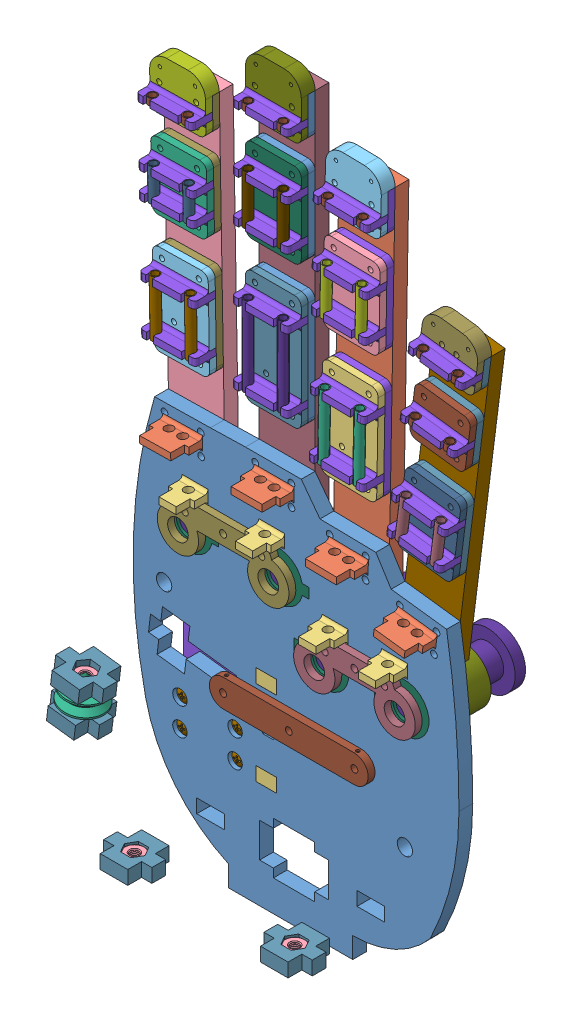
SolidWorks assembly palmTendonRouting_support, configuration Default. Lengths in mm.
Overall size (100.53 213.84 64.07).
220 component instances, 54 part files, 133 mates.
Components (placement in the parent):
- palmUp-1: palmUp [Default] at (29.1174 30.4931 80.2216) size (94.52 113.2 4)
- driverBaseFrame1-1: driverBaseFrame1 [Default] at (-2.9175 115.1932 80.2216) x (0.999847 0.017467 0) z (0.017467 -0.999847 0) size (11.5 12 4)
- driverBaseFrame1-2: driverBaseFrame1 [Default] at (23.5924 115.6931 80.2216) x (1 0 0) z (0 -1 0) size (11.5 12 4)
- driverBaseFrame1-3: driverBaseFrame1 [Default] at (45.1535 108.3901 80.2216) x (0.999848 -0.017452 0) z (-0.017452 -0.999848 0) size (11.5 12 4)
- driverBaseFrame1-4: driverBaseFrame1 [Default] at (65.1211 100.8452 80.2216) x (0.992117 -0.125312 0) z (-0.125312 -0.992117 0) size (11.5 12 4)
- driverBaseFrame2-1: driverBaseFrame2 [Default] at (-1948.2383 102.6443 -1374.6625) x (1 0 0) z (0 -1 0) size (7.5 12 4)
- driverBaseFrame2-2: driverBaseFrame2 [Default] at (1983.3157 100.6443 -1374.6625) x (-1 0 0) z (0 1 0) size (7.5 12 4)
- driverBaseFrame2-4: driverBaseFrame2 [Default] at (-1907.6963 87.8147 -1374.6625) x (1 0 0) z (0 -1 0) size (7.5 12 4)
- driverBaseFrame2-5: driverBaseFrame2 [Default] at (-1890.412 87.8147 -1374.6625) x (1 0 0) z (0 -1 0) size (7.5 12 4)
- index-1: index [Default] at (-52.494 173.2306 -0.0096) x (-0.999847 -0.017467 0) z (0 0 -1) size (16.2 99.16 12.01)
  - indexElastomer-1: indexElastomer [Default] at (-62.4059 -67.241 -80.2312) size (16.2 94.16 4)
  - indexPIP-1: indexPIP [Default] at (-62.4059 -42.8945 -84.2312) size (16.2 26.26 2)
  - indexMIP-1: indexMIP [Default] at (-62.4059 -8.6345 -84.2312) size (16.2 19.45 2)
  - indexDIP-1: indexDIP [Default] at (-62.4059 16.8205 -84.2312) size (16.2 14.95 4)
  - tubeDriver-6: tubeDriver [Default] at (-62.4059 20.8205 -80.2312) x (1 0 0) z (0 1 0) size (16.2 6 4)
  - tubeDriver-7: tubeDriver [Default] at (-62.4059 3.8205 -80.2312) x (1 0 0) z (0 1 0) size (16.2 6 4)
  - tubeDriver-8: tubeDriver [Default] at (-62.4059 -3.6345 -80.2312) x (1 0 0) z (0 1 0) size (16.2 6 4)
  - tubeDriver-9: tubeDriver [Default] at (-62.4059 -23.6345 -80.2312) x (1 0 0) z (0 1 0) size (16.2 6 4)
  - tubeDriver-10: tubeDriver [Default] at (-62.4059 -37.8945 -80.2312) x (1 0 0) z (0 1 0) size (16.2 6 4)
  - indexTube1-1: indexTube1 [Default] at (-49.2059 -21.6345 -86.4812) x (-0.964902 0 0.26261) z (0 -1 0) size (2.5 2.5 16.26)
  - indexTube1-2: indexTube1 [Default] at (-59.4059 -21.6345 -86.4812) x (-0.775159 0 0.631766) z (0 -1 0) size (2.5 2.5 16.26)
  - indexTube2-1: indexTube2 [Default] at (-49.2059 5.8205 -86.4812) x (0.360054 0 0.932932) z (0 -1 0) size (2.5 2.5 9.46)
  - indexTube2-2: indexTube2 [Default] at (-59.4059 5.8205 -86.4812) x (-0.658969 0 -0.75217) z (0 -1 0) size (2.5 2.5 9.46)
  - commonFingersTube-1: commonFingersTube [Default] at (-49.2059 22.8205 -86.4812) x (-0.856421 0 0.516277) z (0 -1 0) size (2.5 2.5 2)
  - commonFingersTube-2: commonFingersTube [Default] at (-59.4059 22.8205 -86.4812) x (-0.999231 0 0.039215) z (0 -1 0) size (2.5 2.5 2)
  - indexJointBase-1: indexJointBase [Default] at (-62.4059 -67.241 -82.2312) size (16.2 69.66 2)
- middle-1: middle [Default] at (34.8412 175.8995 -30.6566) size (16.2 113.14 12)
  - middleElastomer-1: middleElastomer [Default] at (-13.8237 -68.7065 106.8781) size (16.2 108.14 4)
  - middlePIP-1: middlePIP [Default] at (-13.8237 -44.2065 110.8781) size (16.2 33.21 2)
  - middleMIP-1: middleMIP [Default] at (-13.8237 -2.9965 110.8781) size (16.2 24.45 2)
  - middleDIP-1: middleDIP [Default] at (-5.7237 27.4535 110.8781) size (16.2 16.98 4)
  - tubeDriver-2: tubeDriver [Default] at (-13.8237 33.4535 110.8781) x (1 0 0) z (0 -1 0) size (16.2 6 4)
  - tubeDriver-3: tubeDriver [Default] at (-13.8237 16.4535 110.8781) x (1 0 0) z (0 -1 0) size (16.2 6 4)
  - tubeDriver-4: tubeDriver [Default] at (-13.8237 4.0035 110.8781) x (1 0 0) z (0 -1 0) size (16.2 6 4)
  - tubeDriver-5: tubeDriver [Default] at (-13.8237 -15.9965 110.8781) x (1 0 0) z (0 -1 0) size (16.2 6 4)
  - tubeDriver-6: tubeDriver [Default] at (-13.8237 -37.2065 110.8781) x (1 0 0) z (0 -1 0) size (16.2 6 4)
  - middleTube1-1: middleTube1 [Default] at (-10.8237 -39.2065 117.1281) x (1 0 0) z (0 1 0) size (2.5 2.5 23.21)
  - middleTube1-2: middleTube1 [Default] at (-0.6237 -39.2065 117.1281) x (1 0 0) z (0 1 0) size (2.5 2.5 23.21)
  - middleTube2-1: middleTube2 [Default] at (-10.8237 2.0035 117.1281) x (1 0 0) z (0 1 0) size (2.5 2.5 14.45)
  - middleTube2-2: middleTube2 [Default] at (-0.6237 2.0035 117.1281) x (1 0 0) z (0 1 0) size (2.5 2.5 14.45)
  - commonFingersTube-1: commonFingersTube [Default] at (-10.8237 31.4535 117.1281) x (1 0 0) z (0 1 0) size (2.5 2.5 2)
  - commonFingersTube-2: commonFingersTube [Default] at (-0.6237 31.4535 117.1281) x (1 0 0) z (0 1 0) size (2.5 2.5 2)
  - middleJointBase-1: middleJointBase [Default] at (-13.8237 -70.2065 110.8781) size (16.2 83.64 2)
- ring-1: ring [Default] at (23.5555 139.8292 -20.9472) x (-0.999848 0.017452 0) z (0 0 -1) size (16.2 107.96 12)
  - ringElastomer-1: ringElastomer [Default] at (-35.7683 -39.5573 -101.1688) size (16.2 102.96 4)
  - ringPIP-1: ringPIP [Default] at (-35.7683 -15.0573 -105.1688) size (16.2 29.14 2)
  - ringMIP-1: ringMIP [Default] at (-35.7683 22.0827 -105.1688) size (16.2 23.53 2)
  - ringDIP-1: ringDIP [Default] at (-19.5683 51.6077 -101.1688) x (-1 0 0) z (0 0 -1) size (16.2 16.8 4)
  - tubeDriver-6: tubeDriver [Default] at (-35.7683 55.6077 -101.1688) x (1 0 0) z (0 1 0) size (16.2 6 4)
  - tubeDriver-7: tubeDriver [Default] at (-35.7683 38.6077 -101.1688) x (1 0 0) z (0 1 0) size (16.2 6 4)
  - tubeDriver-8: tubeDriver [Default] at (-35.7683 27.0827 -101.1688) x (1 0 0) z (0 1 0) size (16.2 6 4)
  - tubeDriver-9: tubeDriver [Default] at (-35.7683 7.0827 -101.1688) x (1 0 0) z (0 1 0) size (16.2 6 4)
  - tubeDriver-10: tubeDriver [Default] at (-35.7683 -10.0573 -101.1688) x (1 0 0) z (0 1 0) size (16.2 6 4)
  - ringTube1-1: ringTube1 [Default] at (-22.5683 9.0827 -107.4188) x (1 0 0) z (0 -1 0) size (2.5 2.5 19.14)
  - ringTube1-2: ringTube1 [Default] at (-32.7683 9.0827 -107.4188) x (1 0 0) z (0 -1 0) size (2.5 2.5 19.14)
  - ringTube2-1: ringTube2 [Default] at (-22.5683 40.6077 -107.4188) x (1 0 0) z (0 -1 0) size (2.5 2.5 13.53)
  - ringTube2-2: ringTube2 [Default] at (-32.7683 40.6077 -107.4188) x (1 0 0) z (0 -1 0) size (2.5 2.5 13.53)
  - commonFingersTube-1: commonFingersTube [Default] at (-22.5683 57.6077 -107.4188) x (1 0 0) z (0 -1 0) size (2.5 2.5 2)
  - commonFingersTube-2: commonFingersTube [Default] at (-32.7683 57.6077 -107.4188) x (-0.448476 0 -0.893795) z (0 -1 0) size (2.5 2.5 2)
  - ringJointBase-1: ringJointBase [Default] at (-35.7683 -41.0573 -103.1688) size (16.2 78.46 2)
- pinky-1: pinky [Default] at (76.9532 164.3008 -0.0182) x (0.992117 -0.125312 0) z (0 0 1) size (16.2 89.09 12)
  - pinkyElastomer-1: pinkyElastomer [Default] at (-6.1366 -72.9381 76.2397) size (16.2 84.09 4)
  - pinkyPIP-1: pinkyPIP [Default] at (-6.1366 -48.4381 80.2397) size (16.2 21.74 2)
  - pinkyMIP-1: pinkyMIP [Default] at (-6.1366 -18.6981 80.2397) size (16.2 14.64 2)
  - pinkyDIP-1: pinkyDIP [Default] at (-6.1366 1.9469 80.2397) size (16.2 14.21 4)
  - tubeDriver-5: tubeDriver [Default] at (-6.1366 7.9469 80.2397) x (1 0 0) z (0 -1 0) size (16.2 6 4)
  - tubeDriver-7: tubeDriver [Default] at (-6.1366 -31.6981 80.2397) x (1 0 0) z (0 -1 0) size (16.2 6 4)
  - tubeDriver-8: tubeDriver [Default] at (-6.1366 -41.4381 80.2397) x (1 0 0) z (0 -1 0) size (16.2 6 4)
  - pinkyTube1-1: pinkyTube1 [Default] at (-3.1366 -43.4381 86.4897) x (1 0 0) z (0 1 0) size (2.5 2.5 11.74)
  - pinkyTube1-2: pinkyTube1 [Default] at (7.0634 -43.4381 86.4897) x (1 0 0) z (0 1 0) size (2.5 2.5 11.74)
  - tubeDriver-10: tubeDriver [Default] at (-6.1366 -10.3756 80.2397) x (1 0 0) z (0 -1 0) size (16.2 6 4)
  - commonFingersTube-1: commonFingersTube [Default] at (-3.1366 5.9469 86.4897) x (1 0 0) z (0 1 0) size (2.5 2.5 2)
  - commonFingersTube-2: commonFingersTube [Default] at (7.0634 5.9469 86.4897) x (1 0 0) z (0 1 0) size (2.5 2.5 2)
  - pinkyJointBase-1: pinkyJointBase [Default] at (-6.1366 -74.4381 80.2397) size (16.2 59.59 2)
  - commonFingersTube-3: commonFingersTube [Default] at (-3.1366 -12.3756 86.4897) x (1 0 0) z (0 1 0) size (2.5 2.5 2)
  - commonFingersTube-4: commonFingersTube [Default] at (7.0634 -12.3756 86.4897) x (1 0 0) z (0 1 0) size (2.5 2.5 2)
- buttonBase-1: buttonBase [Default] at (67.2648 77.3147 84.2216) x (0 -1 0) z (0 0 -1) size (16 16.84 9)
- buttonBase-2: buttonBase [Default] at (43.9805 77.3147 84.2216) x (0 -1 0) z (0 0 -1) size (16 16.84 9)
- buttonBase-3: buttonBase [Default] at (30.6388 92.1443 84.2216) x (0 1 0) z (0 0 -1) size (16 16.84 9)
- buttonBase-4: buttonBase [Default] at (4.4385 92.1443 84.2216) x (0 1 0) z (0 0 -1) size (16 16.84 9)
- buttonFrame-1: buttonFrame [Default] at (67.2648 77.3147 67.2216) x (-0.367754 -0.929923 0) z (0 0 1) size (16 16 8)
- buttonFrame-2: buttonFrame [Default] at (43.9805 77.3147 67.2216) x (-0.367754 -0.929923 0) z (0 0 1) size (16 16 8)
- buttonFrame-3: buttonFrame [Default] at (4.4385 92.1443 67.2216) x (-0.366273 -0.930508 0) z (0 0 1) size (16 16 8)
- buttonFrame-4: buttonFrame [Default] at (30.6388 92.1443 67.2216) x (-0.366273 -0.930508 0) z (0 0 1) size (16 16 8)
- buttonAxle-1: buttonAxle [Default] at (67.2648 77.3147 57.2216) size (16 16 27)
- buttonAxle-2: buttonAxle [Default] at (4.4385 92.1443 57.2216) size (16 16 27)
- buttonAxle-3: buttonAxle [Default] at (43.9805 77.3147 57.2216) x (-1 0 0) z (0 0 1) size (16 16 27)
- buttonAxle-4: buttonAxle [Default] at (30.6388 92.1443 57.2216) x (-1 0 0) z (0 0 1) size (16 16 27)
- parallel pin hardened_din-1: parallel pin hardened_din [Parallel Pin ISO 8734 - 2 x 14 - A - St] at (67.5898 69.8147 71.2178) x (0 1 0) z (-0.989175 0 -0.14674) size (14 2 2)
- parallel pin hardened_din-2: parallel pin hardened_din [Parallel Pin ISO 8734 - 2 x 14 - A - St] at (43.6555 69.8147 71.2178) x (0 1 0) z (-0.930242 0 0.366947) size (14 2 2)
- parallel pin hardened_din-3: parallel pin hardened_din [Parallel Pin ISO 8734 - 2 x 14 - A - St] at (4.7635 98.6443 71.2178) x (0 -1 0) z (0 0 1) size (14 2 2)
- parallel pin hardened_din-4: parallel pin hardened_din [Parallel Pin ISO 8734 - 2 x 14 - A - St] at (30.3138 98.6443 71.2178) x (0 -1 0) z (-0.297916 0 0.954592) size (14 2 2)
- Assem1-1: Assem1 [Default] at (68.1098 77.3321 69.8525) x (0.982823 0 0.184551) z (0 -1 0) size (9.07 23.24 9)
  - Spring Part-1: Spring Part [Default] at origin size (9 1 4.5)
  - Spring Part-7: Spring Part [Default] at (-0.0474 0.6138 0) x (0.988155 0.15346 0) z (0 0 -1) size (9 1 4.5)
  - Spring Part-8: Spring Part [Default] at (-0.0474 1.8415 0) x (0.988155 -0.15346 0) z (0 0 1) size (9 1 4.5)
  - Spring Part-9: Spring Part [Default] at (-0.0474 3.0692 0) x (0.988155 0.15346 0) z (0 0 -1) size (9 1 4.5)
  - Spring Part-10: Spring Part [Default] at (-0.0474 4.2969 0) x (0.988155 -0.15346 0) z (0 0 1) size (9 1 4.5)
  - Spring Part-11: Spring Part [Default] at (-0.0474 5.5246 0) x (0.988155 0.15346 0) z (0 0 -1) size (9 1 4.5)
  - Spring Part-12: Spring Part [Default] at (-0.0474 6.7522 0) x (0.988155 -0.15346 0) z (0 0 1) size (9 1 4.5) (hidden)
  - Spring Part-13: Spring Part [Default] at (-0.0474 7.9799 0) x (0.988155 0.15346 0) z (0 0 -1) size (9 1 4.5) (hidden)
  - Spring Part-14: Spring Part [Default] at (-0.0474 9.2076 0) x (0.988155 -0.15346 0) z (0 0 1) size (9 1 4.5) (hidden)
  - Spring Part-15: Spring Part [Default] at (-0.0474 10.4353 0) x (0.988155 0.15346 0) z (0 0 -1) size (9 1 4.5) (hidden)
  - Spring Part-16: Spring Part [Default] at (-0.0474 11.663 0) x (0.988155 -0.15346 0) z (0 0 1) size (9 1 4.5) (hidden)
  - Spring Part-17: Spring Part [Default] at (-0.0474 12.8906 0) x (0.988155 0.15346 0) z (0 0 -1) size (9 1 4.5) (hidden)
  - Spring Part-18: Spring Part [Default] at (-0.0474 14.1183 0) x (0.988155 -0.15346 0) z (0 0 1) size (9 1 4.5) (hidden)
  - Spring Part-19: Spring Part [Default] at (-0.0474 15.346 0) x (0.988155 0.15346 0) z (0 0 -1) size (9 1 4.5) (hidden)
  - Spring Part-20: Spring Part [Default] at (-0.0474 16.5737 0) x (0.988155 -0.15346 0) z (0 0 1) size (9 1 4.5) (hidden)
  - Spring Part-21: Spring Part [Default] at (-0.0474 17.8013 0) x (0.988155 0.15346 0) z (0 0 -1) size (9 1 4.5) (hidden)
  - Spring Part-22: Spring Part [Default] at (-0.0474 19.029 0) x (0.988155 -0.15346 0) z (0 0 1) size (9 1 4.5) (hidden)
  - Spring Part-23: Spring Part [Default] at (-0.0474 20.2567 0) x (0.988155 0.15346 0) z (0 0 -1) size (9 1 4.5) (hidden)
  - Spring Part-24: Spring Part [Default] at (-0.0474 21.4844 0) x (0.988155 -0.15346 0) z (0 0 1) size (9 1 4.5) (hidden)
  - Spring Part-25: Spring Part [Default] at (0 22.0982 0) x (1 0 0) z (0 0 -1) size (9 1 4.5) (hidden)
- Assem1-2: Assem1 [Default] at (43.2323 76.9505 75.7945) x (0.961864 0.191525 0.195284) z (-0.195284 0.980747 0) size (9.07 23.24 9)
  - Spring Part-1: Spring Part [Default] at origin size (9 1 4.5)
  - Spring Part-7: Spring Part [Default] at (-0.0474 0.6138 0) x (0.988155 0.15346 0) z (0 0 -1) size (9 1 4.5)
  - Spring Part-8: Spring Part [Default] at (-0.0474 1.8415 0) x (0.988155 -0.15346 0) z (0 0 1) size (9 1 4.5)
  - Spring Part-9: Spring Part [Default] at (-0.0474 3.0692 0) x (0.988155 0.15346 0) z (0 0 -1) size (9 1 4.5)
  - Spring Part-10: Spring Part [Default] at (-0.0474 4.2969 0) x (0.988155 -0.15346 0) z (0 0 1) size (9 1 4.5)
  - Spring Part-11: Spring Part [Default] at (-0.0474 5.5246 0) x (0.988155 0.15346 0) z (0 0 -1) size (9 1 4.5)
  - Spring Part-12: Spring Part [Default] at (-0.0474 6.7522 0) x (0.988155 -0.15346 0) z (0 0 1) size (9 1 4.5) (hidden)
  - Spring Part-13: Spring Part [Default] at (-0.0474 7.9799 0) x (0.988155 0.15346 0) z (0 0 -1) size (9 1 4.5) (hidden)
  - Spring Part-14: Spring Part [Default] at (-0.0474 9.2076 0) x (0.988155 -0.15346 0) z (0 0 1) size (9 1 4.5) (hidden)
  - Spring Part-15: Spring Part [Default] at (-0.0474 10.4353 0) x (0.988155 0.15346 0) z (0 0 -1) size (9 1 4.5) (hidden)
  - Spring Part-16: Spring Part [Default] at (-0.0474 11.663 0) x (0.988155 -0.15346 0) z (0 0 1) size (9 1 4.5) (hidden)
  - Spring Part-17: Spring Part [Default] at (-0.0474 12.8906 0) x (0.988155 0.15346 0) z (0 0 -1) size (9 1 4.5) (hidden)
  - Spring Part-18: Spring Part [Default] at (-0.0474 14.1183 0) x (0.988155 -0.15346 0) z (0 0 1) size (9 1 4.5) (hidden)
  - Spring Part-19: Spring Part [Default] at (-0.0474 15.346 0) x (0.988155 0.15346 0) z (0 0 -1) size (9 1 4.5) (hidden)
  - Spring Part-20: Spring Part [Default] at (-0.0474 16.5737 0) x (0.988155 -0.15346 0) z (0 0 1) size (9 1 4.5) (hidden)
  - Spring Part-21: Spring Part [Default] at (-0.0474 17.8013 0) x (0.988155 0.15346 0) z (0 0 -1) size (9 1 4.5) (hidden)
  - Spring Part-22: Spring Part [Default] at (-0.0474 19.029 0) x (0.988155 -0.15346 0) z (0 0 1) size (9 1 4.5) (hidden)
  - Spring Part-23: Spring Part [Default] at (-0.0474 20.2567 0) x (0.988155 0.15346 0) z (0 0 -1) size (9 1 4.5) (hidden)
  - Spring Part-24: Spring Part [Default] at (-0.0474 21.4844 0) x (0.988155 -0.15346 0) z (0 0 1) size (9 1 4.5) (hidden)
  - Spring Part-25: Spring Part [Default] at (0 22.0982 0) x (1 0 0) z (0 0 -1) size (9 1 4.5) (hidden)
- Assem1-3: Assem1 [Default] at (30.4884 91.6348 76.0217) x (1 0 0) z (0 1 0) size (9.07 23.24 9)
  - Spring Part-1: Spring Part [Default] at origin size (9 1 4.5)
  - Spring Part-7: Spring Part [Default] at (-0.0474 0.6138 0) x (0.988155 0.15346 0) z (0 0 -1) size (9 1 4.5)
  - Spring Part-8: Spring Part [Default] at (-0.0474 1.8415 0) x (0.988155 -0.15346 0) z (0 0 1) size (9 1 4.5)
  - Spring Part-9: Spring Part [Default] at (-0.0474 3.0692 0) x (0.988155 0.15346 0) z (0 0 -1) size (9 1 4.5)
  - Spring Part-10: Spring Part [Default] at (-0.0474 4.2969 0) x (0.988155 -0.15346 0) z (0 0 1) size (9 1 4.5)
  - Spring Part-11: Spring Part [Default] at (-0.0474 5.5246 0) x (0.988155 0.15346 0) z (0 0 -1) size (9 1 4.5)
  - Spring Part-12: Spring Part [Default] at (-0.0474 6.7522 0) x (0.988155 -0.15346 0) z (0 0 1) size (9 1 4.5) (hidden)
  - Spring Part-13: Spring Part [Default] at (-0.0474 7.9799 0) x (0.988155 0.15346 0) z (0 0 -1) size (9 1 4.5) (hidden)
  - Spring Part-14: Spring Part [Default] at (-0.0474 9.2076 0) x (0.988155 -0.15346 0) z (0 0 1) size (9 1 4.5) (hidden)
  - Spring Part-15: Spring Part [Default] at (-0.0474 10.4353 0) x (0.988155 0.15346 0) z (0 0 -1) size (9 1 4.5) (hidden)
  - Spring Part-16: Spring Part [Default] at (-0.0474 11.663 0) x (0.988155 -0.15346 0) z (0 0 1) size (9 1 4.5) (hidden)
  - Spring Part-17: Spring Part [Default] at (-0.0474 12.8906 0) x (0.988155 0.15346 0) z (0 0 -1) size (9 1 4.5) (hidden)
  - Spring Part-18: Spring Part [Default] at (-0.0474 14.1183 0) x (0.988155 -0.15346 0) z (0 0 1) size (9 1 4.5) (hidden)
  - Spring Part-19: Spring Part [Default] at (-0.0474 15.346 0) x (0.988155 0.15346 0) z (0 0 -1) size (9 1 4.5) (hidden)
  - Spring Part-20: Spring Part [Default] at (-0.0474 16.5737 0) x (0.988155 -0.15346 0) z (0 0 1) size (9 1 4.5) (hidden)
  - Spring Part-21: Spring Part [Default] at (-0.0474 17.8013 0) x (0.988155 0.15346 0) z (0 0 -1) size (9 1 4.5) (hidden)
  - Spring Part-22: Spring Part [Default] at (-0.0474 19.029 0) x (0.988155 -0.15346 0) z (0 0 1) size (9 1 4.5) (hidden)
  - Spring Part-23: Spring Part [Default] at (-0.0474 20.2567 0) x (0.988155 0.15346 0) z (0 0 -1) size (9 1 4.5) (hidden)
  - Spring Part-24: Spring Part [Default] at (-0.0474 21.4844 0) x (0.988155 -0.15346 0) z (0 0 1) size (9 1 4.5) (hidden)
  - Spring Part-25: Spring Part [Default] at (0 22.0982 0) x (1 0 0) z (0 0 -1) size (9 1 4.5) (hidden)
- Assem1-4: Assem1 [Default] at (3.643 90.6443 75.9726) x (1 0 0) z (0 1 0) size (9.07 23.24 9)
  - Spring Part-1: Spring Part [Default] at origin size (9 1 4.5)
  - Spring Part-7: Spring Part [Default] at (-0.0474 0.6138 0) x (0.988155 0.15346 0) z (0 0 -1) size (9 1 4.5)
  - Spring Part-8: Spring Part [Default] at (-0.0474 1.8415 0) x (0.988155 -0.15346 0) z (0 0 1) size (9 1 4.5)
  - Spring Part-9: Spring Part [Default] at (-0.0474 3.0692 0) x (0.988155 0.15346 0) z (0 0 -1) size (9 1 4.5)
  - Spring Part-10: Spring Part [Default] at (-0.0474 4.2969 0) x (0.988155 -0.15346 0) z (0 0 1) size (9 1 4.5)
  - Spring Part-11: Spring Part [Default] at (-0.0474 5.5246 0) x (0.988155 0.15346 0) z (0 0 -1) size (9 1 4.5)
  - Spring Part-12: Spring Part [Default] at (-0.0474 6.7522 0) x (0.988155 -0.15346 0) z (0 0 1) size (9 1 4.5) (hidden)
  - Spring Part-13: Spring Part [Default] at (-0.0474 7.9799 0) x (0.988155 0.15346 0) z (0 0 -1) size (9 1 4.5) (hidden)
  - Spring Part-14: Spring Part [Default] at (-0.0474 9.2076 0) x (0.988155 -0.15346 0) z (0 0 1) size (9 1 4.5) (hidden)
  - Spring Part-15: Spring Part [Default] at (-0.0474 10.4353 0) x (0.988155 0.15346 0) z (0 0 -1) size (9 1 4.5) (hidden)
  - Spring Part-16: Spring Part [Default] at (-0.0474 11.663 0) x (0.988155 -0.15346 0) z (0 0 1) size (9 1 4.5) (hidden)
  - Spring Part-17: Spring Part [Default] at (-0.0474 12.8906 0) x (0.988155 0.15346 0) z (0 0 -1) size (9 1 4.5) (hidden)
  - Spring Part-18: Spring Part [Default] at (-0.0474 14.1183 0) x (0.988155 -0.15346 0) z (0 0 1) size (9 1 4.5) (hidden)
  - Spring Part-19: Spring Part [Default] at (-0.0474 15.346 0) x (0.988155 0.15346 0) z (0 0 -1) size (9 1 4.5) (hidden)
  - Spring Part-20: Spring Part [Default] at (-0.0474 16.5737 0) x (0.988155 -0.15346 0) z (0 0 1) size (9 1 4.5) (hidden)
  - Spring Part-21: Spring Part [Default] at (-0.0474 17.8013 0) x (0.988155 0.15346 0) z (0 0 -1) size (9 1 4.5) (hidden)
  - Spring Part-22: Spring Part [Default] at (-0.0474 19.029 0) x (0.988155 -0.15346 0) z (0 0 1) size (9 1 4.5) (hidden)
  - Spring Part-23: Spring Part [Default] at (-0.0474 20.2567 0) x (0.988155 0.15346 0) z (0 0 -1) size (9 1 4.5) (hidden)
  - Spring Part-24: Spring Part [Default] at (-0.0474 21.4844 0) x (0.988155 -0.15346 0) z (0 0 1) size (9 1 4.5) (hidden)
  - Spring Part-25: Spring Part [Default] at (0 22.0982 0) x (1 0 0) z (0 0 -1) size (9 1 4.5) (hidden)
- SupportPulleyPalmUpAssem-1: SupportPulleyPalmUpAssem [Default] at (18.0404 39.4745 49.5054) size (10 28.63 11.6)
  - supportPulleyPalmUp2-1: supportPulleyPalmUp2 [Default] at (10.0404 13.9256 23.1162) size (7.5 28.63 2)
  - supportPulleyPalmUp-1: supportPulleyPalmUp [Default] at (12.0404 26.3656 34.7162) x (-1 0 0) z (0 -1 0) size (10 11.6 4)
  - supportPulleyPalmUp-2: supportPulleyPalmUp [Default] at (12.0404 1.7356 34.7162) x (-1 0 0) z (0 -1 0) size (10 11.6 4)
- hex nut style 1 gradeab_din-1: hex nut style 1 gradeab_din [Hexagon Nut ISO 4032 - M3 - D - S] at (27.442 52.7975 82.6216) x (0 1 0) z (0 0 1) size (5.5 6.35 2.4)
- plain washer 6902 type abc_din-1: plain washer 6902 type abc_din [DIN 6902-C3.2] at (28.0808 53.4001 80.2216) x (0 0 -1) z (0.195239 0.980756 0) size (0.8 7 7)
- pulley-1: pulley [Default] at (28.0808 53.4001 75.4216) x (0.991013 -0.133768 0) z (0 0 1) size (12 12 4)
- plain washer 6902 type abc_din-2: plain washer 6902 type abc_din [DIN 6902-C3.2] at (28.0808 53.4001 75.4216) x (0 0 -1) z (0.978291 0.207235 0) size (0.8 7 7)
- socket head cap screw 4762_din-1: socket head cap screw 4762_din [ISO 4762 M3 x 10 --- 10S] at (28.0808 53.4001 69.6216) x (0 0 1) z (-0.999894 -0.01457 0) size (13 5.5 5.5)
- baseHerkulex-1: baseHerkulex [Default] at (-4.9352 30.4931 70.2216) size (31 58.5 17.5)
- pan head cross recess screw_din-1: pan head cross recess screw_din [ISO 7045 - M2 x 10 - Z --- 10S] at (18.0174 47.3687 83.8216) x (0 0 -1) z (0.086476 0.996254 0) size (11.57 4 4)
- pan head cross recess screw_din-2: pan head cross recess screw_din [ISO 7045 - M2 x 10 - Z --- 10S] at (18.0174 39.3687 83.8216) x (0 0 -1) z (-0.029913 -0.999553 0) size (11.57 4 4)
- pan head cross recess screw_din-3: pan head cross recess screw_din [ISO 7045 - M2 x 10 - Z --- 10S] at (2.0174 39.3687 83.8216) x (0 0 -1) z (1 0 0) size (11.57 4 4)
- pan head cross recess screw_din-4: pan head cross recess screw_din [ISO 7045 - M2 x 10 - Z --- 10S] at (2.0174 47.3687 83.8216) x (0 0 -1) z (1 0 0) size (11.57 4 4)
- hex nut style 1 gradeab_din-2: hex nut style 1 gradeab_din [Hexagon Nut ISO 4032 - M2 - D - S] at (2.0174 39.3687 72.2216) x (0.792425 -0.60997 0) z (0 0 1) size (4 4.62 1.6)
- hex nut style 1 gradeab_din-3: hex nut style 1 gradeab_din [Hexagon Nut ISO 4032 - M2 - D - S] at (18.0174 47.3687 72.2216) x (0.098807 -0.995107 0) z (0 0 1) size (4 4.62 1.6)
- hex nut style 1 gradeab_din-4: hex nut style 1 gradeab_din [Hexagon Nut ISO 4032 - M2 - D - S] at (2.0174 47.3687 72.2216) size (4 4.62 1.6)
- hex nut style 1 gradeab_din-5: hex nut style 1 gradeab_din [Hexagon Nut ISO 4032 - M2 - D - S] at (18.0174 39.3687 72.2216) size (4 4.62 1.6)
- plasticSpacer-1: plasticSpacer [Default] at (2.0174 47.3687 76.2216) size (6 6 4)
- plasticSpacer-2: plasticSpacer [Default] at (18.0174 47.3687 76.2216) size (6 6 4)
- plasticSpacer-3: plasticSpacer [Default] at (18.0174 39.3687 76.2216) x (0.106039 0.994362 0) z (0 0 1) size (6 6 4)
- plasticSpacer-4: plasticSpacer [Default] at (2.0174 39.3687 76.2216) x (0.99764 -0.068656 0) z (0 0 1) size (6 6 4)
- whiffleetree-1: whiffleetree [Default] at (16.2286 39.1819 47.2015) x (1 0.000009 0) z (0 0 1) size (74.83 77 2)
  - mainBar-1: mainBar [Default] at (20.3524 18.4625 38.0201) size (46.08 8 2)
  - dynema1-1: dynema1 [Default] at (1.3104 55.9625 39.0201) x (0.250397 0 -0.968143) z (0 -1 0) size (1 1 34) (hidden)
  - barIndexMiddle-1: barIndexMiddle [Default] at (1.3104 58.4625 38.0201) size (38.2 14.5 2)
  - dynema2-1: dynema2 [Default] at (39.3944 21.9625 39.0201) x (0.365635 0 0.930758) z (0 1 0) size (1 1 19.17) (hidden)
  - barMiddlePinky-1: barMiddlePinky [Default] at (39.3944 43.6325 38.0201) size (35.28 14.5 2)
  - dynema3-1: dynema3 [Default] at (20.3524 14.9625 39.0201) x (0.922872 0 -0.385106) z (0 -1 0) size (1 1 30.5) (hidden)
- pulleyInsidePalmAssembled-1: pulleyInsidePalmAssembled [Default] at (-4.9042 46.692 121.0316) x (0.992536 -0.12195 0) z (0.12195 0.992536 0) size (14 13.03 13.6)
  - BasePulleyInsidePalm-1: BasePulleyInsidePalm [Default] at (-0.6961 4.81 7.3798) size (14 12 4)
  - BasePulleyInsidePalm-2: BasePulleyInsidePalm [Default] at (-0.6961 4.81 16.9798) size (14 12 4)
  - pulley-1: pulley [Default] at (3.3039 10.81 12.1798) x (0.995915 0.090298 0) z (0 0 1) size (12 12 4)
  - hex nut style 1 gradeab_din-2: hex nut style 1 gradeab_din [Hexagon Nut ISO 4032 - M3 - D - S] at (3.3916 10.6581 19.3798) x (0.866025 -0.5 0) z (0 0 1) size (5.5 6.35 2.4)
  - hex nut style 1 gradeab_din-3: hex nut style 1 gradeab_din [Hexagon Nut ISO 4032 - M3 - D - S] at (3.2162 10.6581 10.3798) x (0.866025 -0.5 0) z (0 0 1) size (5.5 6.35 2.4)
  - plain washer 6902 type abc_din-1: plain washer 6902 type abc_din [DIN 6902-C3.2] at (3.3039 10.81 16.9798) x (0 0 -1) z (0.829839 0.558003 0) size (0.8 7 7)
  - plain washer 6902 type abc_din-2: plain washer 6902 type abc_din [DIN 6902-C3.2] at (3.3039 10.81 11.3798) x (0 0 1) z (-1 0 0) size (0.8 7 7)
  - slotted set screw cone point_din-1: slotted set screw cone point_din [ISO 7434 - M3 x 12-S] at (3.3916 10.6581 7.9798) x (0 0 1) z (-0.968704 -0.248217 0) size (12 3 3)
- fastenFlangeAssembled-1: fastenFlangeAssembled [Default] at (3.2883 37.3377 94.7418) x (1 0 0) z (0 -1 0) size (14 12 4)
  - BasePulleyInsidePalm-1: BasePulleyInsidePalm [Default] at (3.6005 5.4798 12.8446) size (14 12 4)
  - hex nut style 1 gradeab_din-1: hex nut style 1 gradeab_din [Hexagon Nut ISO 4032 - M3 - D - S] at (7.6882 11.6317 15.8446) x (-0.866025 -0.5 0) z (0 0 1) size (5.5 6.35 2.4)
- fastenFlangeAssembled-2: fastenFlangeAssembled [Default] at (49.7883 37.3377 94.7418) x (1 0 0) z (0 -1 0) size (14 12 4)
  - BasePulleyInsidePalm-1: BasePulleyInsidePalm [Default] at (3.6005 5.4798 12.8446) size (14 12 4)
  - hex nut style 1 gradeab_din-1: hex nut style 1 gradeab_din [Hexagon Nut ISO 4032 - M3 - D - S] at (7.6882 11.6317 15.8446) x (-0.866025 -0.5 0) z (0 0 1) size (5.5 6.35 2.4)
Mates (geometry in assembly coordinates):
- Coincident1: coincident anti-aligned: plane of palmUp-1 through (-1.6321 113.2154 84.2216) normal (-0.017467 0.999847 0); plane of driverBaseFrame1-1 through (-2.8826 113.1935 80.2216) normal (0.017467 -0.999847 0)
- Coincident2: coincident anti-aligned: plane of palmUp-1 through (7.3666 113.3726 84.2216) normal (-0.999847 -0.017467 0); plane of driverBaseFrame1-1 through (7.3666 113.3726 84.2216) normal (0.999847 0.017467 0)
- Coincident3: coincident aligned: plane of palmUp-1 through (143.3195 75.6611 80.2216) normal (0 0 -1); plane of driverBaseFrame1-1 through (-1.6328 113.2154 80.2216) normal (0 0 -1)
- Coincident4: coincident anti-aligned: plane of palmUp-1 through (24.8424 113.6931 84.2216) normal (0 1 0); plane of driverBaseFrame1-2 through (23.5924 113.6931 80.2216) normal (0 -1 0)
- Coincident5: coincident anti-aligned: plane of palmUp-1 through (24.8424 115.6931 84.2216) normal (1 0 0); plane of driverBaseFrame1-2 through (24.8424 113.6931 84.2216) normal (-1 0 0)
- Coincident6: coincident aligned: plane of palmUp-1 through (143.3195 75.6611 80.2216) normal (0 0 -1); plane of driverBaseFrame1-2 through (24.8424 113.6931 80.2216) normal (0 0 -1)
- Coincident7: coincident aligned: plane of palmUp-1 through (143.3195 75.6611 80.2216) normal (0 0 -1); plane of driverBaseFrame1-3 through (46.3684 106.3686 80.2216) normal (0 0 -1)
- Coincident8: coincident anti-aligned: plane of palmUp-1 through (54.952 108.2191 84.2216) normal (-0.017452 -0.999848 0); plane of driverBaseFrame1-3 through (45.1535 108.3901 80.2216) normal (0.017452 0.999848 0)
- Coincident12: coincident anti-aligned: plane of palmUp-1 through (46.4033 108.3683 84.2216) normal (0.999848 -0.017452 0); plane of driverBaseFrame1-3 through (46.3684 106.3686 84.2216) normal (-0.999848 0.017452 0)
- Coincident13: coincident anti-aligned: plane of palmUp-1 through (66.1107 98.7043 84.2216) normal (0.125312 0.992117 0); plane of driverBaseFrame1-4 through (64.8705 98.861 80.2216) normal (-0.125312 -0.992117 0)
- Coincident14: coincident aligned: plane of palmUp-1 through (143.3195 75.6611 80.2216) normal (0 0 -1); plane of driverBaseFrame1-4 through (66.1107 98.7043 80.2216) normal (0 0 -1)
- Coincident15: coincident anti-aligned: plane of palmUp-1 through (66.3613 100.6886 84.2216) normal (0.992117 -0.125312 0); plane of driverBaseFrame1-4 through (66.1107 98.7043 84.2216) normal (-0.992117 0.125312 0)
- Coincident16: coincident anti-aligned: plane of palmUp-1 through (3.9385 100.6443 84.2216) normal (0 1 0); plane of driverBaseFrame2-1 through (-1948.2383 100.6443 -1374.6625) normal (0 -1 0)
- Coincident17: coincident aligned: plane of palmUp-1 through (143.3195 75.6611 80.2216) normal (0 0 -1); plane of driverBaseFrame2-1 through (3.9385 100.6443 80.2216) normal (0 0 -1)
- Coincident18: coincident anti-aligned: plane of palmUp-1 through (3.9385 102.6443 84.2216) normal (1 0 0); plane of driverBaseFrame2-1 through (3.9385 100.6443 84.2216) normal (-1 0 0)
- Distance1: distance = 0 mm aligned: plane of palmUp-1 through (143.3195 75.6611 80.2216) normal (0 0 -1); plane of driverBaseFrame2-2 through (31.1388 102.6443 80.2216) normal (0 0 -1)
- Coincident20: coincident anti-aligned: plane of palmUp-1 through (31.1388 100.6443 84.2216) normal (-1 0 0); plane of driverBaseFrame2-2 through (31.1388 102.6443 84.2216) normal (1 0 0)
- Coincident21: coincident anti-aligned: plane of palmUp-1 through (26.1388 102.6443 84.2216) normal (0 -1 0); plane of driverBaseFrame2-2 through (1983.3157 102.6443 -1374.6625) normal (0 1 0)
- Coincident22: coincident anti-aligned: plane of palmUp-1 through (44.4805 85.8147 84.2216) normal (0 1 0); plane of driverBaseFrame2-4 through (-1907.6963 85.8147 -1374.6625) normal (0 -1 0)
- Coincident23: coincident aligned: plane of palmUp-1 through (143.3195 75.6611 80.2216) normal (0 0 -1); plane of driverBaseFrame2-4 through (44.4805 85.8147 80.2216) normal (0 0 -1)
- Coincident24: coincident anti-aligned: plane of palmUp-1 through (49.4805 85.8147 84.2216) normal (-1 0 0); plane of driverBaseFrame2-4 through (49.4805 85.8147 84.2216) normal (1 0 0)
- Coincident25: coincident anti-aligned: plane of palmUp-1 through (61.7648 85.8147 84.2216) normal (0 1 0); plane of driverBaseFrame2-5 through (-1890.412 85.8147 -1374.6625) normal (0 -1 0)
- Coincident26: coincident aligned: plane of palmUp-1 through (143.3195 75.6611 80.2216) normal (0 0 -1); plane of driverBaseFrame2-5 through (61.7648 85.8147 80.2216) normal (0 0 -1)
- Coincident27: coincident anti-aligned: plane of palmUp-1 through (61.7648 87.8147 84.2216) normal (1 0 0); plane of driverBaseFrame2-5 through (61.7648 85.8147 84.2216) normal (-1 0 0)
- Concentric1: concentric anti-aligned: cylinder of palmUp-1 through (8.0553 116.8851 84.2216) axis (0 0 -1) radius 0.975; cylinder of index-1/indexElastomer-1 through (8.0553 116.8851 76.2216) axis (0 0 1) radius 0.5
- Concentric2: concentric anti-aligned: cylinder of palmUp-1 through (8.1601 110.886 84.2216) axis (0 0 -1) radius 0.975; cylinder of index-1/indexElastomer-1 through (8.1601 110.886 76.2216) axis (0 0 1) radius 0.5
- Coincident28: coincident anti-aligned: plane of palmUp-1 through (143.3195 75.6611 80.2216) normal (0 0 -1); plane of index-1/indexElastomer-1 through (11.0769 107.0899 80.2216) normal (0 0 1)
- Concentric3: concentric aligned: cylinder of palmUp-1 through (23.8674 111.1931 84.2216) axis (0 0 -1) radius 0.975; cylinder of middle-1/middleElastomer-1 through (23.8674 111.1931 80.2216) axis (0 0 -1) radius 0.52
- Concentric4: concentric aligned: circle of palmUp-1; circle of middle-1/middleElastomer-1
- Coincident29: coincident anti-aligned: plane of palmUp-1 through (143.3195 75.6611 80.2216) normal (0 0 -1); plane of middle-1/middleElastomer-1 through (21.0174 107.1931 80.2216) normal (0 0 1)
- Concentric5: concentric aligned: circle of palmUp-1; cylinder of ring-1/ringElastomer-1 through (45.3499 103.886 76.2216) axis (0 0 1) radius 0.5
- Concentric6: concentric anti-aligned: cylinder of palmUp-1 through (45.4546 109.8851 84.2216) axis (0 0 -1) radius 0.975; cylinder of ring-1/ringElastomer-1 through (45.4546 109.8851 76.2216) axis (0 0 1) radius 0.5
- Coincident30: coincident anti-aligned: plane of palmUp-1 through (143.3195 75.6611 80.2216) normal (0 0 -1); plane of ring-1/ringElastomer-1 through (58.628 99.6536 80.2216) normal (0 0 1)
- Concentric7: concentric aligned: cylinder of palmUp-1 through (65.0537 96.318 84.2216) axis (0 0 -1) radius 0.975; cylinder of pinky-1/pinkyElastomer-1 through (65.0537 96.318 80.2216) axis (0 0 -1) radius 0.52
- Concentric8: concentric anti-aligned: cylinder of palmUp-1 through (65.8055 102.2707 84.2216) axis (0 0 -1) radius 0.975; circle of pinky-1/pinkyElastomer-1
- Coincident31: coincident anti-aligned: plane of palmUp-1 through (143.3195 75.6611 80.2216) normal (0 0 -1); plane of pinky-1/pinkyElastomer-1 through (61.7249 92.7066 80.2216) normal (0 0 1)
- Concentric9: concentric anti-aligned: cylinder of palmUp-1 through (67.2648 77.3147 84.2216) axis (0 0 -1) radius 7; cylinder of buttonBase-1 through (67.2648 77.3147 80.2216) axis (0 0 1) radius 7
- Coincident32: coincident: moEndPointRef_w of palmUp-1; plane of buttonBase-1 through (60.4274 75.8147 80.2216) normal (0 -1 0)
- Coincident40: coincident anti-aligned: plane of palmUp-1 through (143.3195 75.6611 80.2216) normal (0 0 -1); plane of buttonBase-1 through (67.2648 77.3147 80.2216) normal (0 0 1)
- Concentric10: concentric anti-aligned: cylinder of palmUp-1 through (43.9805 77.3147 84.2216) axis (0 0 -1) radius 7; cylinder of buttonBase-2 through (43.9805 77.3147 80.2216) axis (0 0 1) radius 7
- Coincident34: coincident anti-aligned: plane of palmUp-1 through (35.1431 75.8147 84.2216) normal (0 1 0); plane of buttonBase-2 through (37.1431 75.8147 80.2216) normal (0 -1 0)
- Coincident41: coincident anti-aligned: plane of palmUp-1 through (143.3195 75.6611 80.2216) normal (0 0 -1); plane of buttonBase-2 through (43.9805 77.3147 80.2216) normal (0 0 1)
- Concentric11: concentric anti-aligned: cylinder of palmUp-1 through (30.6388 92.1443 84.2216) axis (0 0 -1) radius 7; cylinder of buttonBase-3 through (30.6388 92.1443 80.2216) axis (0 0 1) radius 7
- Coincident37: coincident anti-aligned: plane of palmUp-1 through (39.4762 90.6443 84.2216) normal (0 1 0); plane of buttonBase-3 through (38.497 90.6443 80.2216) normal (0 -1 0)
- Coincident42: coincident anti-aligned: plane of palmUp-1 through (143.3195 75.6611 80.2216) normal (0 0 -1); plane of buttonBase-3 through (30.6388 92.1443 80.2216) normal (0 0 1)
- Concentric13: concentric anti-aligned: cylinder of palmUp-1 through (4.4385 92.1443 84.2216) axis (0 0 -1) radius 7; cylinder of buttonBase-4 through (4.4385 92.1443 80.2216) axis (0 0 1) radius 7
- Coincident39: coincident anti-aligned: plane of palmUp-1 through (11.2759 93.6443 84.2216) normal (0 -1 0); plane of buttonBase-4 through (11.2759 93.6443 80.2216) normal (0 1 0)
- Coincident43: coincident anti-aligned: plane of palmUp-1 through (143.3195 75.6611 80.2216) normal (0 0 -1); plane of buttonBase-4 through (4.4385 92.1443 80.2216) normal (0 0 1)
- Concentric14: concentric anti-aligned: cylinder of buttonBase-1 through (67.2648 77.3147 75.2216) axis (0 0 1) radius 5; cylinder of buttonFrame-1 through (67.2648 77.3147 75.2216) axis (0 0 -1) radius 5
- Coincident44: coincident aligned: plane of buttonBase-1 through (63.4238 70.2971 76.2216) normal (0.877201 -0.480124 0); plane of buttonFrame-1 through (63.4238 70.2971 72.7216) normal (0.877201 -0.480124 0)
- Coincident60: coincident anti-aligned: plane of buttonBase-1 through (67.2648 77.3147 75.2216) normal (0 0 -1); plane of buttonFrame-1 through (67.2648 77.3147 75.2216) normal (0 0 1)
- Concentric15: concentric anti-aligned: cylinder of buttonBase-2 through (43.9805 77.3147 75.2216) axis (0 0 1) radius 5; cylinder of buttonFrame-2 through (43.9805 77.3147 75.2216) axis (0 0 -1) radius 5
- Coincident46: coincident: line of buttonBase-2 through (41.5799 72.9287 77.2216) axis (-0.480124 -0.877201 0); plane of buttonFrame-2 through (40.1395 70.2971 72.7216) normal (0.877201 -0.480124 0)
- Coincident61: coincident anti-aligned: plane of buttonBase-2 through (43.9805 77.3147 75.2216) normal (0 0 -1); plane of buttonFrame-2 through (43.9805 77.3147 75.2216) normal (0 0 1)
- Concentric16: concentric anti-aligned: cylinder of buttonBase-3 through (30.6388 92.1443 75.2216) axis (0 0 1) radius 5; cylinder of buttonFrame-4 through (30.6388 92.1443 75.2216) axis (0 0 -1) radius 5
- Parallel1: parallel aligned: plane of buttonBase-4 through (0.6087 85.1206 76.2216) normal (0.877964 -0.478727 0); plane of buttonFrame-4 through (26.809 85.1206 72.7216) normal (0.877964 -0.478727 0)
- Coincident63: coincident anti-aligned: plane of buttonBase-4 through (4.4385 92.1443 75.2216) normal (0 0 -1); plane of buttonFrame-4 through (30.6388 92.1443 75.2216) normal (0 0 1)
- Concentric17: concentric anti-aligned: cylinder of buttonBase-4 through (4.4385 92.1443 75.2216) axis (0 0 1) radius 5; cylinder of buttonFrame-3 through (4.4385 92.1443 75.2216) axis (0 0 -1) radius 5
- Coincident50: coincident aligned: plane of buttonBase-4 through (0.6087 85.1206 76.2216) normal (0.877964 -0.478727 0); plane of buttonFrame-3 through (0.6087 85.1206 72.7216) normal (0.877964 -0.478727 0)
- Coincident62: coincident anti-aligned: plane of buttonBase-4 through (4.4385 92.1443 75.2216) normal (0 0 -1); plane of buttonFrame-3 through (4.4385 92.1443 75.2216) normal (0 0 1)
- Concentric18: concentric aligned: cylinder of buttonFrame-1 through (67.2648 77.3147 75.2216) axis (0 0 -1) radius 5; cylinder of buttonAxle-1 through (67.2648 77.3147 74.2216) axis (0 0 -1) radius 4.675
- Distance6: distance = 7 mm anti-aligned: plane of buttonAxle-1 through (67.2648 77.3147 74.2216) normal (0 0 1); plane of buttonFrame-1 through (67.2648 77.3147 67.2216) normal (0 0 -1)
- Concentric19: concentric aligned: cylinder of buttonFrame-2 through (43.9805 77.3147 75.2216) axis (0 0 -1) radius 5; cylinder of buttonAxle-3 through (43.9805 77.3147 74.2216) axis (0 0 -1) radius 4.675
- Distance7: distance = 7 mm anti-aligned: plane of buttonFrame-2 through (43.9805 77.3147 67.2216) normal (0 0 -1); plane of buttonAxle-3 through (43.9805 77.3147 74.2216) normal (0 0 1)
- Concentric20: concentric aligned: cylinder of buttonFrame-4 through (30.6388 92.1443 75.2216) axis (0 0 -1) radius 5; cylinder of buttonAxle-4 through (30.6388 92.1443 74.2216) axis (0 0 -1) radius 4.675
- Distance8: distance = 7 mm anti-aligned: plane of buttonFrame-4 through (30.6388 92.1443 67.2216) normal (0 0 -1); plane of buttonAxle-4 through (30.6388 92.1443 74.2216) normal (0 0 1)
- Concentric21: concentric aligned: cylinder of buttonFrame-3 through (4.4385 92.1443 75.2216) axis (0 0 -1) radius 5; cylinder of buttonAxle-2 through (4.4385 92.1443 74.2216) axis (0 0 -1) radius 4.675
- Distance9: distance = 7 mm anti-aligned: plane of buttonFrame-3 through (4.4385 92.1443 67.2216) normal (0 0 -1); plane of buttonAxle-2 through (4.4385 92.1443 74.2216) normal (0 0 1)
- Concentric22: concentric anti-aligned: cylinder of buttonAxle-1 through (67.5898 69.8147 71.2178) axis (0 1 0) radius 1.225; cylinder of parallel pin hardened_din-1 through (67.5898 63.4647 71.2178) axis (0 -1 0) radius 1
- Distance10: distance = 6 mm aligned: plane of parallel pin hardened_din-1 through (67.7227 69.8147 70.3214) normal (0 -1 0); plane of buttonBase-1 through (60.4274 75.8147 80.2216) normal (0 -1 0)
- Concentric23: concentric aligned: cylinder of buttonAxle-3 through (43.6555 84.8147 71.2178) axis (0 -1 0) radius 1.225; cylinder of parallel pin hardened_din-2 through (43.6555 63.4647 71.2178) axis (0 -1 0) radius 1
- Distance11: distance = 8 mm anti-aligned: plane of parallel pin hardened_din-2 through (43.6555 83.8147 71.2178) normal (0 1 0); plane of buttonBase-2 through (37.1431 75.8147 80.2216) normal (0 -1 0)
- Concentric24: concentric anti-aligned: cylinder of buttonAxle-4 through (30.3138 99.6443 71.2178) axis (0 -1 0) radius 1.225; cylinder of parallel pin hardened_din-4 through (30.3138 104.9943 71.2178) axis (0 1 0) radius 1
- Distance12: distance = 6 mm aligned: plane of parallel pin hardened_din-4 through (30.3138 84.6443 71.2178) normal (0 -1 0); plane of buttonBase-3 through (38.497 90.6443 80.2216) normal (0 -1 0)
- Concentric25: concentric aligned: cylinder of buttonAxle-2 through (4.7635 84.6443 71.2178) axis (0 1 0) radius 1.225; cylinder of parallel pin hardened_din-3 through (4.7635 104.9943 71.2178) axis (0 1 0) radius 1
- Distance13: distance = 6 mm aligned: plane of parallel pin hardened_din-3 through (4.7635 84.6443 71.2178) normal (0 -1 0); plane of buttonBase-4 through (12.2966 90.6443 80.2216) normal (0 -1 0)
- Parallel2: parallel anti-aligned: plane of buttonBase-1 through (60.4274 75.8147 80.2216) normal (0 -1 0); plane of Assem1-1/Spring Part-11 through (70.8151 77.3321 76.6062) normal (0 1 0)
- Parallel3: parallel: line of buttonBase-2 through (36.1224 75.8147 75.2216) axis (0 0 1); plane of Assem1-2/Spring Part-1 through (47.0797 77.7166 76.5756) normal (-0.195284 0.980747 0)
- Parallel4: parallel anti-aligned: plane of buttonBase-3 through (38.497 90.6443 80.2216) normal (0 -1 0); plane of Assem1-3/Spring Part-1 through (34.4884 91.6348 76.0217) normal (0 1 0)
- Coincident59: coincident anti-aligned: plane of buttonBase-4 through (12.2966 90.6443 80.2216) normal (0 -1 0); plane of Assem1-4/Spring Part-1 through (7.643 90.6443 75.9726) normal (0 1 0)
- Coincident64: coincident anti-aligned: plane of palmUp-1 through (30.0808 37.2101 84.2216) normal (0 1 0); plane of SupportPulleyPalmUpAssem-1/supportPulleyPalmUp-2 through (30.0808 37.2101 84.2216) normal (0 -1 0)
- Coincident65: coincident anti-aligned: plane of palmUp-1 through (24.0808 37.2101 84.2216) normal (1 0 0); plane of SupportPulleyPalmUpAssem-1/supportPulleyPalmUp-2 through (24.0808 37.2101 84.2216) normal (-1 0 0)
- Coincident67: coincident anti-aligned: plane of palmUp-1 through (29.1174 50.1994 84.2216) normal (-0.866025 0.5 0); plane of hex nut style 1 gradeab_din-1 through (29.0297 50.0475 80.2216) normal (0.866025 -0.5 0)
- Coincident68: coincident anti-aligned: plane of palmUp-1 through (30.6174 52.7975 84.2216) normal (-0.866025 -0.5 0); plane of hex nut style 1 gradeab_din-1 through (30.6174 52.7975 80.2216) normal (0.866025 0.5 0)
- Coincident69: coincident aligned: plane of palmUp-1 through (143.3195 75.6611 80.2216) normal (0 0 -1); plane of hex nut style 1 gradeab_din-1 through (24.2666 52.7975 80.2216) normal (0 0 -1)
- Concentric26: concentric anti-aligned: cylinder of SupportPulleyPalmUpAssem-1/supportPulleyPalmUp2-1 through (28.0808 53.4001 74.6216) axis (0 0 -1) radius 1.5; cylinder of plain washer 6902 type abc_din-1 through (28.0808 53.4001 79.4216) axis (0 0 1) radius 1.6
- Coincident70: coincident anti-aligned: plane of hex nut style 1 gradeab_din-1 through (24.2666 52.7975 80.2216) normal (0 0 -1); plane of plain washer 6902 type abc_din-1 through (28.0808 53.4001 80.2216) normal (0 0 1)
- Concentric27: concentric aligned: cylinder of SupportPulleyPalmUpAssem-1/supportPulleyPalmUp2-1 through (28.0808 53.4001 74.6216) axis (0 0 -1) radius 1.5; cylinder of pulley-1 through (28.0808 53.4001 77.4216) axis (0 0 -1) radius 1.5
- Coincident71: coincident anti-aligned: plane of plain washer 6902 type abc_din-1 through (28.0808 53.4001 79.4216) normal (0 0 -1); plane of pulley-1 through (28.0808 53.4001 79.4216) normal (0 0 1)
- Concentric28: concentric anti-aligned: cylinder of pulley-1 through (28.0808 53.4001 77.4216) axis (0 0 -1) radius 1.5; cylinder of plain washer 6902 type abc_din-2 through (28.0808 53.4001 74.6216) axis (0 0 1) radius 1.6
- Coincident72: coincident anti-aligned: plane of pulley-1 through (28.0808 53.4001 75.4216) normal (0 0 -1); plane of plain washer 6902 type abc_din-2 through (28.0808 53.4001 75.4216) normal (0 0 1)
- Coincident73: coincident anti-aligned: plane of SupportPulleyPalmUpAssem-1/supportPulleyPalmUp2-1 through (28.0808 53.4001 74.6216) normal (0 0 1); plane of plain washer 6902 type abc_din-2 through (28.0808 53.4001 74.6216) normal (0 0 -1)
- Coincident74: coincident aligned: cylinder of SupportPulleyPalmUpAssem-1/supportPulleyPalmUp2-1 through (28.0808 53.4001 74.6216) axis (0 0 -1) radius 1.5; circle of socket head cap screw 4762_din-1
- Coincident75: coincident anti-aligned: plane of SupportPulleyPalmUpAssem-1/supportPulleyPalmUp2-1 through (28.0808 53.4001 72.6216) normal (0 0 -1); plane of socket head cap screw 4762_din-1 through (28.0407 56.1498 72.6216) normal (0 0 1)
- Concentric29: concentric anti-aligned: cylinder of palmUp-1 through (18.0174 39.3687 84.2216) axis (0 0 -1) radius 1.225; cylinder of baseHerkulex-1 through (18.0174 39.3687 74.2216) axis (0 0 1) radius 1.5
- Concentric31: concentric anti-aligned: cylinder of palmUp-1 through (2.0174 39.3687 84.2216) axis (0 0 -1) radius 1.225; cylinder of baseHerkulex-1 through (2.0174 39.3687 74.2216) axis (0 0 1) radius 1.5
- Distance14: distance = 4 mm anti-aligned: plane of baseHerkulex-1 through (-4.9352 30.4931 76.2216) normal (0 0 1); plane of palmUp-1 through (143.3195 75.6611 80.2216) normal (0 0 -1)
- Concentric32: concentric aligned: circle of palmUp-1; circle of pan head cross recess screw_din-1
- Coincident81: coincident anti-aligned: plane of palmUp-1 through (18.0174 47.3687 82.2216) normal (0 0 1); plane of pan head cross recess screw_din-1 through (17.0212 47.4552 82.2216) normal (0 0 -1)
- Concentric33: concentric aligned: cylinder of palmUp-1 through (18.0174 39.3687 82.2216) axis (0 0 1) radius 2.1; circle of pan head cross recess screw_din-2
- Coincident82: coincident anti-aligned: plane of palmUp-1 through (18.0174 39.3687 82.2216) normal (0 0 1); plane of pan head cross recess screw_din-2 through (19.017 39.3388 82.2216) normal (0 0 -1)
- Concentric34: concentric aligned: cylinder of palmUp-1 through (2.0174 39.3687 82.2216) axis (0 0 1) radius 2.1; circle of pan head cross recess screw_din-3
- Coincident83: coincident anti-aligned: plane of palmUp-1 through (2.0174 39.3687 82.2216) normal (0 0 1); plane of pan head cross recess screw_din-3 through (2.0174 40.3687 82.2216) normal (0 0 -1)
- Concentric35: concentric aligned: cylinder of palmUp-1 through (2.0174 47.3687 82.2216) axis (0 0 1) radius 2.1; circle of pan head cross recess screw_din-4
- Coincident84: coincident anti-aligned: plane of palmUp-1 through (2.0174 47.3687 82.2216) normal (0 0 1); plane of pan head cross recess screw_din-4 through (2.0174 48.3687 82.2216) normal (0 0 -1)
- Concentric36: concentric anti-aligned: cylinder of baseHerkulex-1 through (18.0174 47.3687 74.2216) axis (0 0 1) radius 1.5; circle of hex nut style 1 gradeab_din-3
- Distance27: distance = 2 mm anti-aligned: plane of hex nut style 1 gradeab_din-3 through (20.3155 47.5969 72.2216) normal (0 0 1); plane of baseHerkulex-1 through (-4.9352 30.4931 70.2216) normal (0 0 -1)
- Concentric37: concentric aligned: cylinder of baseHerkulex-1 through (2.0174 47.3687 74.2216) axis (0 0 1) radius 1.5; circle of hex nut style 1 gradeab_din-4
- Distance20: distance = 2 mm anti-aligned: plane of baseHerkulex-1 through (-4.9352 30.4931 70.2216) normal (0 0 -1); plane of hex nut style 1 gradeab_din-4 through (2.0174 49.6781 72.2216) normal (0 0 1)
- Concentric38: concentric aligned: cylinder of baseHerkulex-1 through (18.0174 39.3687 74.2216) axis (0 0 1) radius 1.5; circle of hex nut style 1 gradeab_din-5
- Distance21: distance = 2 mm anti-aligned: plane of baseHerkulex-1 through (-4.9352 30.4931 70.2216) normal (0 0 -1); plane of hex nut style 1 gradeab_din-5 through (18.0174 41.6781 72.2216) normal (0 0 1)
- Concentric39: concentric aligned: cylinder of baseHerkulex-1 through (2.0174 39.3687 74.2216) axis (0 0 1) radius 1.5; circle of hex nut style 1 gradeab_din-2
- Distance22: distance = 2 mm anti-aligned: plane of baseHerkulex-1 through (-4.9352 30.4931 70.2216) normal (0 0 -1); plane of hex nut style 1 gradeab_din-2 through (3.4261 41.1987 72.2216) normal (0 0 1)
- Concentric40: concentric aligned: cylinder of palmUp-1 through (2.0174 47.3687 84.2216) axis (0 0 -1) radius 1.225; cylinder of plasticSpacer-1 through (2.0174 47.3687 80.2216) axis (0 0 -1) radius 2
- Coincident77: coincident anti-aligned: plane of palmUp-1 through (143.3195 75.6611 80.2216) normal (0 0 -1); plane of plasticSpacer-1 through (2.0174 47.3687 80.2216) normal (0 0 1)
- Concentric41: concentric aligned: cylinder of palmUp-1 through (18.0174 47.3687 84.2216) axis (0 0 -1) radius 1.225; cylinder of plasticSpacer-2 through (18.0174 47.3687 80.2216) axis (0 0 -1) radius 2
- Coincident78: coincident anti-aligned: plane of palmUp-1 through (143.3195 75.6611 80.2216) normal (0 0 -1); plane of plasticSpacer-2 through (18.0174 47.3687 80.2216) normal (0 0 1)
- Concentric42: concentric aligned: cylinder of palmUp-1 through (18.0174 39.3687 84.2216) axis (0 0 -1) radius 1.225; cylinder of plasticSpacer-3 through (18.0174 39.3687 80.2216) axis (0 0 -1) radius 2
- Coincident79: coincident anti-aligned: plane of palmUp-1 through (143.3195 75.6611 80.2216) normal (0 0 -1); plane of plasticSpacer-3 through (18.0174 39.3687 80.2216) normal (0 0 1)
- Concentric43: concentric aligned: cylinder of palmUp-1 through (2.0174 39.3687 84.2216) axis (0 0 -1) radius 1.225; cylinder of plasticSpacer-4 through (2.0174 39.3687 80.2216) axis (0 0 -1) radius 2
- Coincident80: coincident anti-aligned: plane of palmUp-1 through (143.3195 75.6611 80.2216) normal (0 0 -1); plane of plasticSpacer-4 through (2.0174 39.3687 80.2216) normal (0 0 1)
- Concentric44: concentric anti-aligned: cylinder of buttonBase-4 through (4.4385 92.1443 81.2216) axis (0 0 1) radius 3.5; cylinder of whiffleetree-1/barIndexMiddle-1 through (4.4383 92.1443 87.2216) axis (0 0 -1) radius 3
- Concentric45: concentric anti-aligned: cylinder of buttonBase-2 through (43.9805 77.3147 81.2216) axis (0 0 1) radius 3.5; cylinder of whiffleetree-1/barMiddlePinky-1 through (43.9805 77.3147 87.2216) axis (0 0 -1) radius 3
- Distance28: distance = 1 mm anti-aligned: plane of whiffleetree-1/barMiddlePinky-1 through (43.9805 77.3147 85.2216) normal (0 0 -1); plane of palmUp-1 through (143.3195 75.6611 84.2216) normal (0 0 1)
- Coincident85: coincident anti-aligned: plane of palmUp-1 through (-4.6107 54.7887 84.2216) normal (0.992536 -0.12195 0); plane of pulleyInsidePalmAssembled-1/BasePulleyInsidePalm-1 through (-4.2073 58.0717 104.2216) normal (-0.992536 0.12195 0)
- Distance29: distance = 20 mm anti-aligned: plane of pulleyInsidePalmAssembled-1/BasePulleyInsidePalm-1 through (3.733 57.0961 104.2216) normal (0 0 -1); plane of palmUp-1 through (143.3195 75.6611 84.2216) normal (0 0 1)
- Coincident87: coincident anti-aligned: plane of palmUp-1 through (4.9037 66.6245 84.2216) normal (-0.12195 -0.992536 0); plane of pulleyInsidePalmAssembled-1/BasePulleyInsidePalm-2 through (-3.0366 67.6001 116.2216) normal (0.12195 0.992536 0)
- Coincident91: coincident: plane of palmUp-1 through (6.8888 20.4931 84.2216) normal (1 0 0); plane of fastenFlangeAssembled-1/BasePulleyInsidePalm-1 through (6.8888 20.4931 104.2216) normal (-1 0 0)
- Coincident92: coincident: plane of palmUp-1 through (14.8888 20.4931 84.2216) normal (0 1 0); plane of fastenFlangeAssembled-1/BasePulleyInsidePalm-1 through (6.8888 20.4931 100.2216) normal (0 -1 0)
- Distance31: distance = 20 mm anti-aligned: plane of palmUp-1 through (143.3195 75.6611 84.2216) normal (0 0 1); plane of fastenFlangeAssembled-1/BasePulleyInsidePalm-1 through (3.8888 20.4931 104.2216) normal (0 0 -1)
- Coincident94: coincident: plane of palmUp-1 through (53.3888 24.4931 84.2216) normal (1 0 0); plane of fastenFlangeAssembled-2/BasePulleyInsidePalm-1 through (53.3888 20.4931 104.2216) normal (-1 0 0)
- Coincident95: coincident: plane of palmUp-1 through (53.3888 20.4931 84.2216) normal (0 1 0); plane of fastenFlangeAssembled-2/BasePulleyInsidePalm-1 through (53.3888 20.4931 100.2216) normal (0 -1 0)
- Distance32: distance = 20 mm anti-aligned: plane of palmUp-1 through (143.3195 75.6611 84.2216) normal (0 0 1); plane of fastenFlangeAssembled-2/BasePulleyInsidePalm-1 through (61.3888 20.4931 104.2216) normal (0 0 -1)
